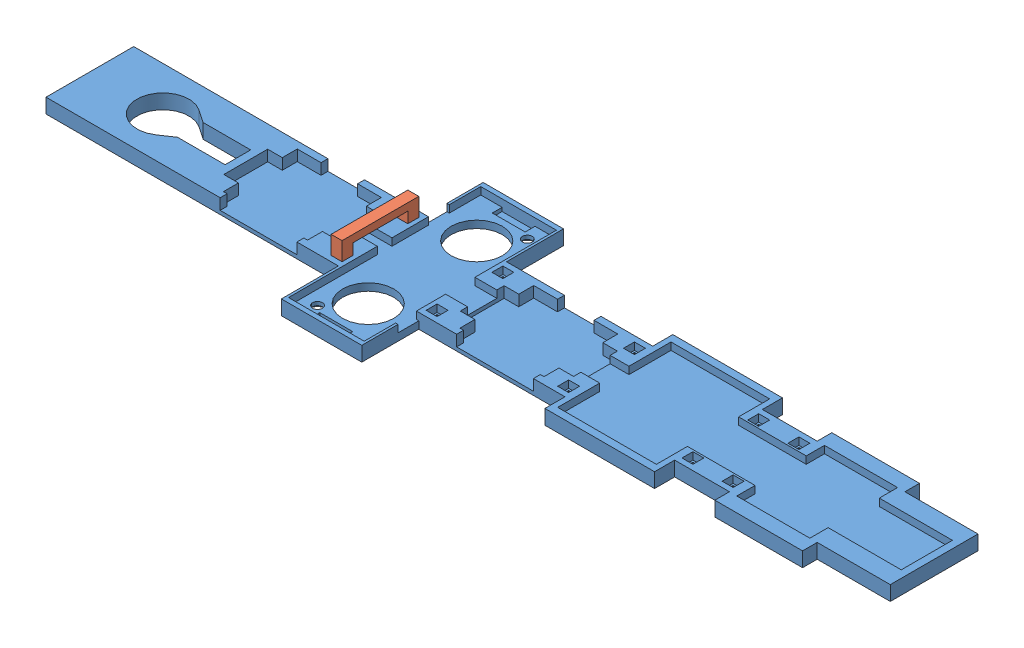
SolidWorks assembly Assem1, configuration Default. Lengths in mm.
Overall size (231 9 55.2).
3 component instances, 3 part files, 6 mates.
Components (placement in the parent):
- Bottom-1: Bottom [Default] at (-68.5293 196.8383 287.2136) size (231 4 55.2)
- Stopper top-1: Stopper top [Default] at (10.9707 198.8383 264.7136) x (0 0 1) z (-1 0 0) size (21 7 3)
- stopper_bottom-2: stopper_bottom [Default] at (7.9707 196.8383 264.2136) x (0 0 1) z (-1 0 0) size (22 3 3)
Mates (geometry in assembly coordinates):
- Coincident3: coincident anti-aligned: plane of Bottom-1 through (7.9707 198.8383 264.7136) normal (0 0 1); plane of Stopper top-1 through (7.9707 198.8383 264.7136) normal (0 0 -1)
- Coincident10: coincident anti-aligned: plane of Bottom-1 through (10.9707 198.8383 264.7136) normal (-1 0 0); plane of stopper_bottom-2 through (10.9707 197.8383 264.2136) normal (1 0 0)
- Coincident11: coincident anti-aligned: plane of Bottom-1 through (7.9707 197.8383 264.2136) normal (0 0 1); plane of stopper_bottom-2 through (7.9707 197.8383 264.2136) normal (0 0 -1)
- Coincident12: coincident aligned: plane of Bottom-1 through (-68.5293 196.8383 287.2136) normal (0 -1 0); plane of stopper_bottom-2 through (7.9707 196.8383 264.2136) normal (0 -1 0)
- Coincident13: coincident anti-aligned: plane of Bottom-1 through (-68.5293 198.8383 287.2136) normal (0 1 0); plane of Stopper top-1 through (7.9707 198.8383 285.7136) normal (0 -1 0)
- Coincident14: coincident anti-aligned: plane of Bottom-1 through (7.9707 198.8383 285.7136) normal (1 0 0); plane of Stopper top-1 through (7.9707 198.8383 264.7136) normal (-1 0 0)
